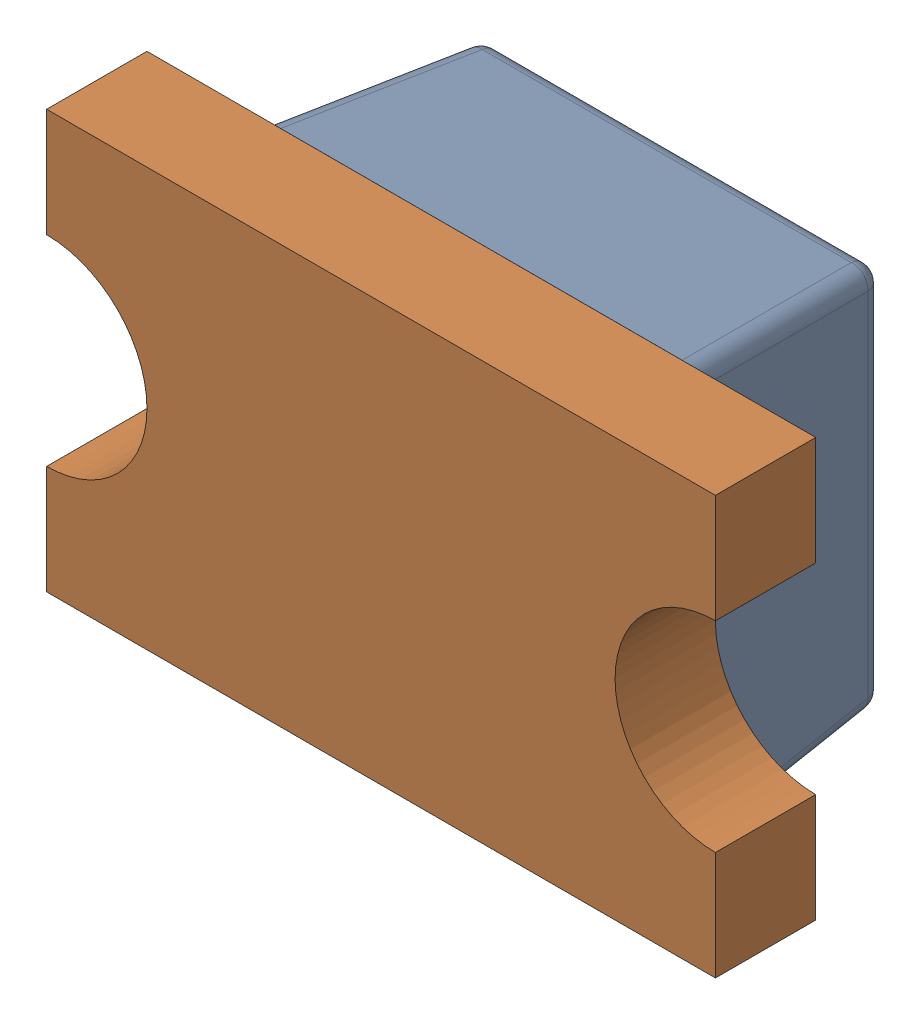
SolidWorks assembly D9_2, configuration Default. Lengths in mm.
Overall size (2 1.25 0.9).
2 component instances, 2 part files, 0 mates.
Components (placement in the parent):
- LED 0805 Lens RED-1: LED 0805 Lens RED [Default] at (113.9109 95.663 -1.2114) x (-1 0 0) z (0 -1 0) size (1.3 0.6 1.25)
- LED 0805 Base RED-1: LED 0805 Base RED [Default] at (113.9109 95.663 -1.2114) x (-1 0 0) z (0 -1 0) size (2 0.4 1.25)
